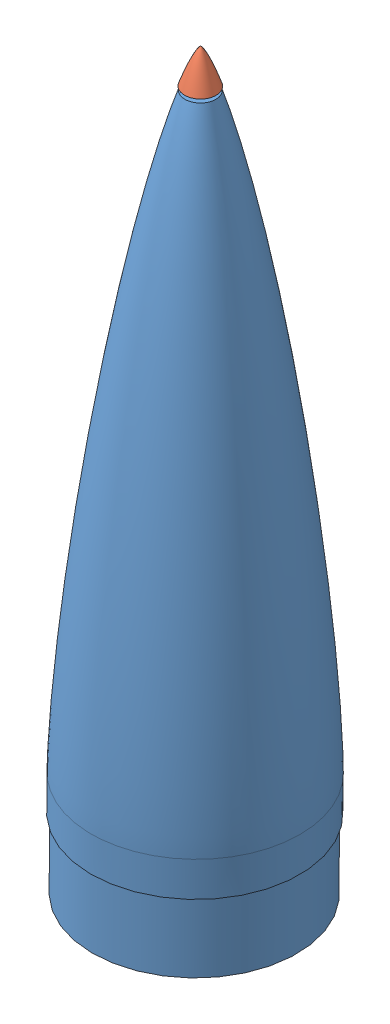
SolidWorks assembly NoseCone, configuration Default. Lengths in mm.
Overall size (313.65 1073.69 304.8).
2 component instances, 2 part files, 1 mates.
Components (placement in the parent):
- NoseCone-1: NoseCone [Default] at (1025.2987 1041.6077 1017.0299) x (-0.008727 -0.999962 0) z (0 0 1) size (1016 304.8 304.8)
- NoseConeTip-2: NoseConeTip [Default] at (1025.3438 1046.7761 1017.0299) x (0.000404 -1 0.000472) z (-0.051616 0.00045 0.998667) size (51.36 45.99 45.99)
Mates (geometry in assembly coordinates):
- Concentric2: concentric aligned: cylinder of NoseCone-1 through (1025.8367 1103.2501 1017.0299) axis (0.008727 0.999962 0) radius 6.35; circle of NoseConeTip-2
